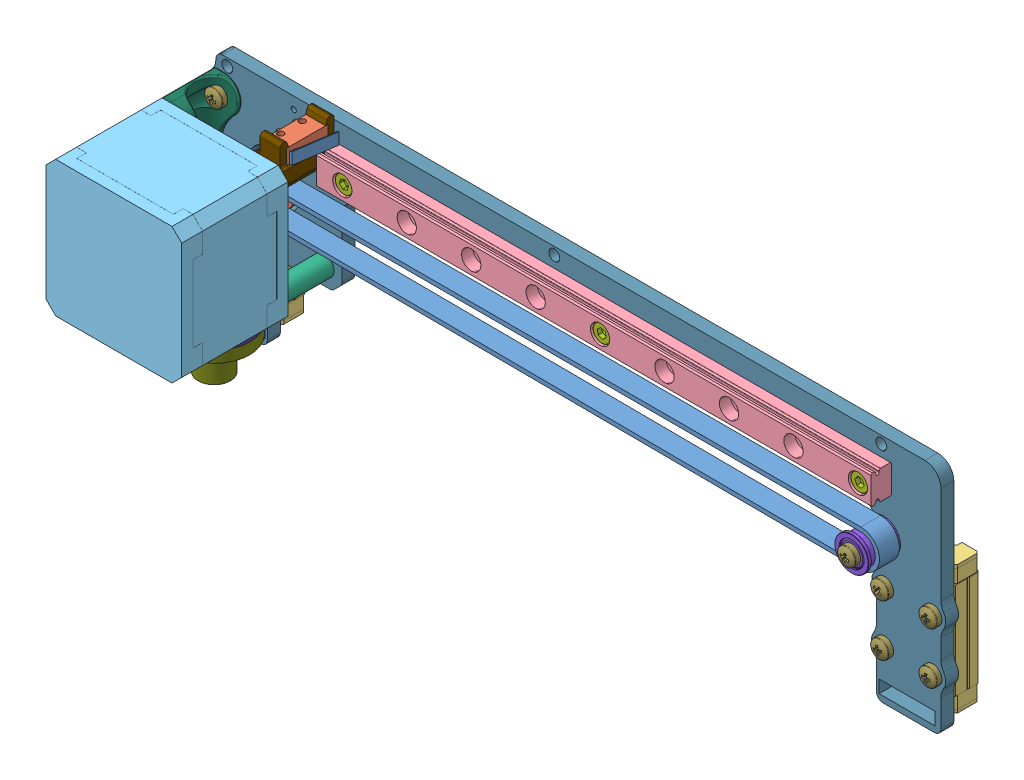
SolidWorks assembly X Bridge assembly mirror2, configuration Valor predeterminado. Lengths in mm.
Overall size (239.98 80.93 61.8).
47 component instances, 20 part files, 82 mates.
Components (placement in the parent):
- Mini CF X Belt (MXL)-2: Mini CF X Belt (MXL) [Default] at (-299.1991 -275.8743 16.2803) x (0.005742 0.999984 0) z (0 0 1) size (11.6 200.95 6.2)
- Timing Gear 15 touth MXL-2: Timing Gear 15 touth MXL [Valor predeterminado] at (-184.7535 53.485 6.1803) x (0 0 1) z (-0.766371 -0.642398 0) size (14.3 14.8 14.8)
- Rail MGN9-4: Rail MGN9 [Default] at (-196.8317 30.5 0.9403) x (-1 0 0) z (0 1 0) size (20 8.06 39.97)
- Mini CF TRACK-2: Mini CF TRACK [Valor predeterminado] at (-347.093 68.74 8.4403) x (0 -1 0) z (0 0 1) size (9 171.98 6.5)
- Steper Motor (42HD0401-24, 34mm)-2: Steper Motor (42HD0401-24, 34mm) [Default] at (-184.7535 53.485 58.1803) x (0 1 0) z (0 0 -1) size (42.1 42.1 48.5)
- Rail MGN9-5: Rail MGN9 [Default] at (12.172 30.5 0.9403) x (-1 0 0) z (0 1 0) size (20 8.06 39.97)
- Mini CF X Bridge spacer-4: Mini CF X Bridge spacer [Valor predeterminado] at (-191.3535 42.9506 25.1803) x (0.844919 0.534894 0) z (0 0 -1) size (6.2 6.2 16.74)
- ISO 4762 M3 x 10 --- 10N-4: ISO 4762 M3 x 10 --- 10N [ISO 4762 M3 x 8 --- 8N] at (2.907 68.74 14.4403) x (0 0 -1) z (-0.081652 -0.996661 0) size (11 5.5 5.5)
- ISO 4762 M3 x 10 --- 10N-5: ISO 4762 M3 x 10 --- 10N [ISO 4762 M3 x 8 --- 8N] at (-77.093 68.74 14.4403) x (0 0 -1) z (-0.673418 0.739262 0) size (11 5.5 5.5)
- ISO 4762 M3 x 10 --- 10N-6: ISO 4762 M3 x 10 --- 10N [ISO 4762 M3 x 8 --- 8N] at (-157.093 68.74 14.4403) x (0 0 -1) z (-0.266118 0.96394 0) size (11 5.5 5.5)
- Bearing assembly-2: Bearing assembly [Default] at (5.1399 52.94 11.6421) x (0 0 -1) z (-0.016512 -0.999864 0) size (10.71 13.72 13.72)
  - F603HZZ-1: F603HZZ [Default] at origin size (5 10.49 10.49)
    - F603HZZ_SOLID_1-1: F603HZZ_SOLID_1 [Default] at origin size (5 10.49 10.49)
    - F603HZZ_SOLID_2-1: F603HZZ_SOLID_2 [Default] at origin size (3.13 7.92 8.2)
    - F603HZZ_SOLID_3-1: F603HZZ_SOLID_3 [Default] at origin size (5 4.24 4.24)
  - F603HZZ-2: F603HZZ [Default] at (-5.0038 0 0) x (-1 0 0) z (0 -0.922978 -0.384852) size (5 10.49 10.49)
    - F603HZZ_SOLID_1-1: F603HZZ_SOLID_1 [Default] at origin size (5 10.49 10.49)
    - F603HZZ_SOLID_2-1: F603HZZ_SOLID_2 [Default] at origin size (3.13 7.92 8.2)
    - F603HZZ_SOLID_3-1: F603HZZ_SOLID_3 [Default] at origin size (5 4.24 4.24)
  - plain washer 10673 type snl_iso-1: plain washer 10673 type snl_iso [ISO 10673-3.2-S] at (2.4018 0 0) x (1 0 0) z (0 0.016518 0.999864) size (0.8 7 7)
- ISO 7045 - M3 x 20 - Z --- 20N-33: ISO 7045 - M3 x 20 - Z --- 20N [ISO 7045 - M3 x 16 - Z --- 16N] at (5.1399 52.94 21.5478) x (0 0 -1) z (-0.206204 -0.978509 0) size (18.35 5.6 5.6)
- hex thin nut chamfered gradeab_iso-7: hex thin nut chamfered gradeab_iso [Hexagon Thin Nut ISO - 4035 - M3 - N] at (2.907 68.74 2.6403) x (0.999802 0.019878 0) z (0 0 -1) size (5.5 6.35 1.8)
- hex thin nut chamfered gradeab_iso-8: hex thin nut chamfered gradeab_iso [Hexagon Thin Nut ISO - 4035 - M3 - N] at (-77.093 68.74 2.6403) x (0.866237 0.499633 0) z (0 0 -1) size (5.5 6.35 1.8)
- hex thin nut chamfered gradeab_iso-9: hex thin nut chamfered gradeab_iso [Hexagon Thin Nut ISO - 4035 - M3 - N] at (5.1399 52.94 2.6403) x (0.866025 0.5 0) z (0 0 -1) size (5.5 6.35 1.8)
- ISO 7045 - M3 x 20 - Z --- 20N-34: ISO 7045 - M3 x 20 - Z --- 20N [ISO 7045 - M3 x 6 - Z --- 6N] at (-204.3317 22.5 10.8403) x (0 0 -1) z (-0.901363 0.433064 0) size (8.35 5.6 5.6)
- ISO 7045 - M3 x 20 - Z --- 20N-35: ISO 7045 - M3 x 20 - Z --- 20N [ISO 7045 - M3 x 6 - Z --- 6N] at (-204.3317 38.5 10.8403) x (0 0 -1) z (0.229638 -0.973276 0) size (8.35 5.6 5.6)
- ISO 7045 - M3 x 20 - Z --- 20N-36: ISO 7045 - M3 x 20 - Z --- 20N [ISO 7045 - M3 x 6 - Z --- 6N] at (-189.2615 38.4288 10.8403) x (0 0 -1) z (-0.98537 -0.170431 0) size (8.35 5.6 5.6)
- ISO 7045 - M3 x 20 - Z --- 20N-37: ISO 7045 - M3 x 20 - Z --- 20N [ISO 7045 - M3 x 6 - Z --- 6N] at (-189.3317 22.5 10.8403) x (0 0 -1) z (0.979425 0.201808 0) size (8.35 5.6 5.6)
- ISO 7045 - M3 x 20 - Z --- 20N-38: ISO 7045 - M3 x 20 - Z --- 20N [ISO 7045 - M3 x 6 - Z --- 6N] at (19.672 22.5 10.8403) x (0 0 -1) z (0.000007 -1 0) size (8.35 5.6 5.6)
- ISO 7045 - M3 x 20 - Z --- 20N-39: ISO 7045 - M3 x 20 - Z --- 20N [ISO 7045 - M3 x 6 - Z --- 6N] at (4.672 38.5 10.8403) x (0 0 -1) z (-0.506009 -0.862528 0) size (8.35 5.6 5.6)
- ISO 7045 - M3 x 20 - Z --- 20N-40: ISO 7045 - M3 x 20 - Z --- 20N [ISO 7045 - M3 x 6 - Z --- 6N] at (4.672 22.5 10.8403) x (0 0 -1) z (0.179665 -0.983728 0) size (8.35 5.6 5.6)
- ISO 7045 - M3 x 20 - Z --- 20N-41: ISO 7045 - M3 x 20 - Z --- 20N [ISO 7045 - M3 x 6 - Z --- 6N] at (19.672 38.5 10.8403) x (0 0 -1) z (0.000007 -1 0) size (8.35 5.6 5.6)
- ISO 7045 - M3 x 20 - Z --- 20N-42: ISO 7045 - M3 x 20 - Z --- 20N [ISO 7045 - M3 x 25 - Z --- 25N] at (-169.2535 37.985 2.0403) x (0 0 1) z (-0.966631 -0.256173 0) size (27.35 5.6 5.6)
- ISO 7045 - M3 x 20 - Z --- 20N-43: ISO 7045 - M3 x 20 - Z --- 20N [ISO 7045 - M3 x 25 - Z --- 25N] at (-169.2535 68.985 2.0403) x (0 0 1) z (0.45862 0.888632 0) size (27.35 5.6 5.6)
- ISO 7045 - M3 x 20 - Z --- 20N-44: ISO 7045 - M3 x 20 - Z --- 20N [ISO 7045 - M3 x 12 - Z --- 12N] at (-200.2535 37.985 19.7803) x (0 0 1) z (0.558384 0.829583 0) size (14.35 5.6 5.6)
- ISO 7045 - M3 x 20 - Z --- 20N-45: ISO 7045 - M3 x 20 - Z --- 20N [ISO 7045 - M3 x 10 - Z --- 10N] at (-200.2535 68.985 19.7803) x (0 0 1) z (-0.999173 0.040658 0) size (12.35 5.6 5.6)
- ISO 7045 - M3 x 20 - Z --- 20N-46: ISO 7045 - M3 x 20 - Z --- 20N [ISO 7045 - M3 x 8 - Z --- 8N] at (-200.2535 68.985 12.5803) x (0 0 -1) z (0.986089 -0.166217 0) size (10.35 5.6 5.6)
- hex thin nut chamfered gradeab_iso-10: hex thin nut chamfered gradeab_iso [Hexagon Thin Nut ISO - 4035 - M3 - N] at (-157.093 68.74 2.6403) x (-0.706351 -0.707861 0) z (0 0 -1) size (5.5 6.35 1.8)
- Mini CF X Bridge 4-1: Mini CF X Bridge 4 [Valor predeterminado] at (-92.8769 -11.1773 8.4403) x (-1 0 0) z (0 0 -1) size (232.81 71.67 4)
- Mini CF X Motor atachment mirror-1: Mini CF X Motor atachment mirror [Valor predeterminado] at (-92.8769 76.0473 25.1803) x (1 0 0) z (0 0 -1) size (11.14 42.1 17.27)
- Treaded Rod Female assembly-1: Treaded Rod Female assembly [Default] at (-40.0999 9.3907 170.362) x (0.703961 0 -0.710239) z (0 1 0) size (28.31 28.33 17.5)
  - Mini CF Z Treaded Rod Female Special Nut-1: Mini CF Z Treaded Rod Female Special Nut [Default] at origin size (22 22 13.5)
  - Mini CF Z nut atachment-1: Mini CF Z nut atachment [Valor predeterminado] at (142.1229 506.6992 3.5) x (0.703961 -0.710239 0) z (0 0 1) size (22 18.05 4)
- Mini CF X Bridge spacer FOR ENDSTOP-1: Mini CF X Bridge spacer FOR ENDSTOP [Valor predeterminado] at (-153.2368 52.9683 25.1803) x (-1 0 0) z (0 0 -1) size (9.2 14.43 16.74)
- Endstop Assembly (HT-010-1A-250VAC) - small-1: Endstop Assembly (HT-010-1A-250VAC) - small [Default] at (-173.3998 75.5732 12.0816) x (0 0 -1) z (0 -1 0) size (13.8 11.8 5.71)
  - Endstop Actuator (HT-010-1A-250VAC)-1: Endstop Actuator (HT-010-1A-250VAC) [Default] at (-9.3436 7.5264 -0.1798) size (12.8 2.57 3.6)
  - Enstop Base (HT-010-1A-250VAC)-1: Enstop Base (HT-010-1A-250VAC) [Default] at (-1.4636 2.6194 0.1552) size (12.83 9.86 5.71)
Mates (geometry in assembly coordinates):
- Tangente3: tangent: plane of Mini CF X Belt (MXL)-2; cylinder of Timing Gear 15 touth MXL-2 through (0.0938 53.4854 18.24) axis (0 0 -1) radius 3.955
- Concêntrico19: concentric: cylinder of Mini CF X Belt (MXL)-2 through (0.0938 53.4854 5.7905) axis (0 0 1) radius 5.2546; cylinder of Timing Gear 15 touth MXL-2 through (0.0938 53.4854 18.24) axis (0 0 -1) radius 7.4
- Paralelo2: parallel: plane of Mini CF X Belt (MXL)-2; plane of Mini CF TRACK-2 through (652.907 64.24 8.4403) normal (0 -1 0)
- Concentric401058: concentric anti-aligned: cylinder of Mini CF X Belt (MXL)-2 through (-184.7534 53.485 10.0803) axis (0 0 1) radius 3.9546; cylinder of Timing Gear 15 touth MXL-2 through (-184.7535 53.485 22.6803) axis (0 0 -1) radius 7.4
- Distance1: distance = 0.7 mm anti-aligned: plane of Mini CF X Belt (MXL)-2 through (5.1399 52.94 10.0803) normal (0 0 -1); plane of Timing Gear 15 touth MXL-2 through (-189.5072 59.1561 9.3803) normal (0 0 1)
- Concentric401066: concentric anti-aligned: cylinder of Mini CF X Belt (MXL)-2 through (5.1399 52.94 10.0803) axis (0 0 1) radius 4.5; cylinder of Bearing assembly-2/F603HZZ-1/F603HZZ_SOLID_1-1 through (5.1399 52.94 14.3942) axis (0 0 -1) radius 4.4958
- Distance4: distance = 0.1 mm anti-aligned: plane of Mini CF X Belt (MXL)-2 through (-369.8613 52.9396 10.2308) normal (0 0 -1); plane of Bearing assembly-2/F603HZZ-1/F603HZZ_SOLID_1-1 through (5.1399 52.94 10.1308) normal (0 0 1)
- Coincident7871313: coincident: plane of Mini CF X Belt (MXL)-2 through (-185.014 52.94 11.9905) normal (0 0 1); plane of ? through (-185.014 52.94 13.7169) normal (0 0 -1)
- Distância12: distance = 2 mm: plane of Steper Motor (42HD0401-24, 34mm)-2 through (0.0938 53.4854 18.74) normal (0 0 -1); plane of Timing Gear 15 touth MXL-2 through (0.0938 53.4854 3.94) normal (0 0 -1)
- Concêntrico37: concentric aligned: cylinder of Timing Gear 15 touth MXL-2 through (-184.7535 53.485 22.6803) axis (0 0 1) radius 2.5; cylinder of Steper Motor (42HD0401-24, 34mm)-2 through (-184.7535 53.485 9.6803) axis (0 0 1) radius 2.5
- Distance3: distance = 0.5 mm anti-aligned: plane of Timing Gear 15 touth MXL-2 through (-189.5072 59.1561 22.6803) normal (0 0 1); plane of Steper Motor (42HD0401-24, 34mm)-2 through (-184.7535 53.485 23.1803) normal (0 0 -1)
- Concentric401076: concentric anti-aligned: cylinder of Rail MGN9-4 through (-204.3317 22.5 4.4403) axis (0 0 -1) radius 1.25; cylinder of ISO 7045 - M3 x 20 - Z --- 20N-34 through (-204.3317 22.5 36.2403) axis (0 0 1) radius 1.5
- Concêntrico38: concentric aligned: cylinder of Mini CF TRACK-2 through (2.907 68.74 14.9403) axis (0 0 1) radius 3; cylinder of ISO 4762 M3 x 10 --- 10N-4 through (2.907 68.74 46.1903) axis (0 0 1) radius 2.75
- Coincidente189: coincident anti-aligned: plane of Mini CF TRACK-2 through (2.907 66.99 11.4403) normal (0 0 1); plane of ISO 4762 M3 x 10 --- 10N-4 through (5.6478 68.5155 11.4403) normal (0 0 -1)
- Concêntrico39: concentric aligned: cylinder of Mini CF TRACK-2 through (-77.093 68.74 14.9403) axis (0 0 1) radius 3; cylinder of ISO 4762 M3 x 10 --- 10N-5 through (-77.093 68.74 46.1903) axis (0 0 1) radius 2.75
- Coincidente190: coincident anti-aligned: plane of Mini CF TRACK-2 through (-77.093 66.99 11.4403) normal (0 0 1); plane of ISO 4762 M3 x 10 --- 10N-5 through (-79.126 66.8881 11.4403) normal (0 0 -1)
- Concêntrico40: concentric aligned: cylinder of Mini CF TRACK-2 through (-157.093 68.74 14.9403) axis (0 0 1) radius 1.75; cylinder of ISO 4762 M3 x 10 --- 10N-6 through (-157.093 68.74 46.1903) axis (0 0 1) radius 2.75
- Coincidente191: coincident anti-aligned: plane of Mini CF TRACK-2 through (-157.093 66.99 11.4403) normal (0 0 1); plane of ISO 4762 M3 x 10 --- 10N-6 through (-159.7439 68.0082 11.4403) normal (0 0 -1)
- Concêntrico28: concentric anti-aligned: circle of Steper Motor (42HD0401-24, 34mm)-2; circle of Mini CF X Bridge spacer-4
- Concêntrico35: concentric aligned: circle of Steper Motor (42HD0401-24, 34mm)-2; cylinder of Mini CF X Bridge spacer-4 through (-169.2535 37.985 8.4403) axis (0 0 1) radius 3.1
- Concentric401065: concentric aligned: cylinder of ISO 7045 - M3 x 20 - Z --- 20N-33 through (5.1399 52.94 46.9478) axis (0 0 1) radius 1.5; cylinder of Bearing assembly-2/plain washer 10673 type snl_iso-1 through (5.1399 52.94 8.4403) axis (0 0 1) radius 1.6
- Concentric401068: concentric aligned: cylinder of Bearing assembly-2/F603HZZ-2/F603HZZ_SOLID_3-1 through (5.1399 52.94 13.8938) axis (0 0 1) radius 1.4986; cylinder of ISO 7045 - M3 x 20 - Z --- 20N-33 through (5.1399 52.94 46.9478) axis (0 0 1) radius 2.8
- Coincident7871314: coincident anti-aligned: plane of ? through (5.1399 52.94 19.1478) normal (0 0 1); plane of ISO 7045 - M3 x 20 - Z --- 20N-33 through (6.6077 52.6307 19.1478) normal (0 0 -1)
- Parallel3: parallel: plane of Mini CF TRACK-2; plane of Mini CF X Bridge 4-1 through (-92.8769 78.74 4.4403) normal (0 1 0)
- Coincident7871363: coincident anti-aligned: plane of Mini CF TRACK-2 through (652.907 73.24 8.4403) normal (0 0 -1); plane of Mini CF X Bridge 4-1 through (-92.8769 -11.1773 8.4403) normal (0 0 1)
- Concentric401135: concentric anti-aligned: cylinder of ISO 7045 - M3 x 20 - Z --- 20N-35 through (-204.3317 38.5 36.2403) axis (0 0 1) radius 1.5; cylinder of Mini CF X Bridge 4-1 through (-204.3317 38.5 4.4403) axis (0 0 -1) radius 1.6
- Lock2: lock: unknown of Rail MGN9-5; unknown of Mini CF X Bridge 4-1
- Lock3: lock: unknown of Mini CF TRACK-2; unknown of Mini CF X Bridge 4-1
- Lock4: lock: unknown of Rail MGN9-4; unknown of Mini CF X Bridge 4-1
- Concentric401136: concentric aligned: cylinder of ISO 7045 - M3 x 20 - Z --- 20N-33 through (5.1399 52.94 46.9478) axis (0 0 1) radius 1.5; cylinder of Mini CF X Bridge 4-1 through (5.1399 52.94 8.4403) axis (0 0 1) radius 1.6
- Coincident7871368: coincident anti-aligned: plane of Bearing assembly-2/plain washer 10673 type snl_iso-1 through (5.1399 52.94 8.4403) normal (0 0 -1); plane of Mini CF X Bridge 4-1 through (-92.8769 -11.1773 8.4403) normal (0 0 1)
- Concentric401138: concentric anti-aligned: cylinder of Timing Gear 15 touth MXL-2 through (-184.7535 53.485 22.6803) axis (0 0 -1) radius 7.4; cylinder of Mini CF X Bridge 4-1 through (-184.7535 53.485 -1.5597) axis (0 0 1) radius 8.4
- Concentric401142: concentric anti-aligned: cylinder of ISO 4762 M3 x 10 --- 10N-4 through (2.907 68.74 46.1903) axis (0 0 1) radius 1.5; cylinder of Mini CF X Bridge 4-1 through (2.907 68.74 4.4403) axis (0 0 -1) radius 1.6
- Concentric401143: concentric anti-aligned: cylinder of ISO 4762 M3 x 10 --- 10N-6 through (-157.093 68.74 46.1903) axis (0 0 1) radius 1.5; cylinder of Mini CF X Bridge 4-1 through (-157.093 68.74 4.4403) axis (0 0 -1) radius 1.6
- Concentric401144: concentric anti-aligned: cylinder of ISO 7045 - M3 x 20 - Z --- 20N-43 through (-169.2535 68.985 -23.3597) axis (0 0 -1) radius 1.5; cylinder of Mini CF X Bridge 4-1 through (-169.2535 68.985 8.4403) axis (0 0 1) radius 1.6
- Coincident7871370: coincident anti-aligned: plane of ISO 7045 - M3 x 20 - Z --- 20N-43 through (-167.9205 68.2971 4.4403) normal (0 0 1); plane of Mini CF X Bridge 4-1 through (-92.8769 -11.1773 4.4403) normal (0 0 -1)
- Coincident7871371: coincident anti-aligned: plane of Mini CF X Bridge spacer-4 through (-169.2535 37.985 8.4403) normal (0 0 -1); plane of Mini CF X Bridge 4-1 through (-92.8769 -11.1773 8.4403) normal (0 0 1)
- Concentric401145: concentric anti-aligned: cylinder of ISO 7045 - M3 x 20 - Z --- 20N-42 through (-169.2535 37.985 -23.3597) axis (0 0 -1) radius 1.5; cylinder of Mini CF X Bridge 4-1 through (-169.2535 37.985 8.4403) axis (0 0 1) radius 1.6
- Coincident7871372: coincident anti-aligned: plane of ISO 7045 - M3 x 20 - Z --- 20N-42 through (-169.6377 39.4349 4.4403) normal (0 0 1); plane of Mini CF X Bridge 4-1 through (-92.8769 -11.1773 4.4403) normal (0 0 -1)
- Concentric401146: concentric anti-aligned: cylinder of ISO 4762 M3 x 10 --- 10N-5 through (-77.093 68.74 46.1903) axis (0 0 1) radius 1.5; cylinder of hex thin nut chamfered gradeab_iso-8 through (-77.093 68.74 4.4403) axis (0 0 -1) radius 1.25
- Concentric401147: concentric anti-aligned: cylinder of ISO 4762 M3 x 10 --- 10N-4 through (2.907 68.74 46.1903) axis (0 0 1) radius 1.5; cylinder of hex thin nut chamfered gradeab_iso-7 through (2.907 68.74 4.4403) axis (0 0 -1) radius 1.25
- Concentric401148: concentric anti-aligned: circle of ISO 4762 M3 x 10 --- 10N-6; cylinder of hex thin nut chamfered gradeab_iso-10 through (-157.093 68.74 4.4403) axis (0 0 -1) radius 1.25
- Concentric401149: concentric aligned: cylinder of ISO 7045 - M3 x 20 - Z --- 20N-33 through (5.1399 52.94 46.9478) axis (0 0 1) radius 1.5; circle of hex thin nut chamfered gradeab_iso-9
- Coincident7871374: coincident anti-aligned: plane of hex thin nut chamfered gradeab_iso-7 through (2.9701 65.5652 4.4403) normal (0 0 1); plane of Mini CF X Bridge 4-1 through (-92.8769 -11.1773 4.4403) normal (0 0 -1)
- Coincident7871375: coincident anti-aligned: plane of hex thin nut chamfered gradeab_iso-9 through (6.7276 50.19 4.4403) normal (0 0 1); plane of Mini CF X Bridge 4-1 through (-92.8769 -11.1773 4.4403) normal (0 0 -1)
- Coincident7871376: coincident anti-aligned: plane of hex thin nut chamfered gradeab_iso-8 through (-75.5065 65.9893 4.4403) normal (0 0 1); plane of Mini CF X Bridge 4-1 through (-92.8769 -11.1773 4.4403) normal (0 0 -1)
- Coincident7871377: coincident anti-aligned: plane of hex thin nut chamfered gradeab_iso-10 through (-159.3408 70.983 4.4403) normal (0 0 1); plane of Mini CF X Bridge 4-1 through (-92.8769 -11.1773 4.4403) normal (0 0 -1)
- Concentric401150: concentric anti-aligned: cylinder of ISO 7045 - M3 x 20 - Z --- 20N-37 through (-189.3317 22.5 36.2403) axis (0 0 1) radius 1.5; cylinder of Mini CF X Bridge 4-1 through (-189.3317 22.5 4.4403) axis (0 0 -1) radius 1.6
- Concentric401151: concentric anti-aligned: cylinder of ISO 7045 - M3 x 20 - Z --- 20N-34 through (-204.3317 22.5 36.2403) axis (0 0 1) radius 1.5; cylinder of Mini CF X Bridge 4-1 through (-204.3317 22.5 4.4403) axis (0 0 -1) radius 1.6
- Coincident7871378: coincident anti-aligned: plane of ISO 7045 - M3 x 20 - Z --- 20N-34 through (-204.9813 21.148 8.4403) normal (0 0 -1); plane of Mini CF X Bridge 4-1 through (-92.8769 -11.1773 8.4403) normal (0 0 1)
- Coincident7871379: coincident anti-aligned: plane of ISO 7045 - M3 x 20 - Z --- 20N-37 through (-189.6344 23.9691 8.4403) normal (0 0 -1); plane of Mini CF X Bridge 4-1 through (-92.8769 -11.1773 8.4403) normal (0 0 1)
- Tangent5: tangent aligned: cylinder of ISO 7045 - M3 x 20 - Z --- 20N-36 through (-189.2615 38.4288 36.2403) axis (0 0 1) radius 1.5; cylinder of Mini CF X Bridge 4-1 through (-189.3317 38.5 4.4403) axis (0 0 -1) radius 1.6
- Coincident7871380: coincident anti-aligned: plane of ISO 7045 - M3 x 20 - Z --- 20N-36 through (-189.0058 36.9507 8.4403) normal (0 0 -1); plane of Mini CF X Bridge 4-1 through (-92.8769 -11.1773 8.4403) normal (0 0 1)
- Coincident7871381: coincident anti-aligned: plane of Steper Motor (42HD0401-24, 34mm)-2 through (-163.7035 74.535 25.1803) normal (0 0 -1); plane of Mini CF X Motor atachment mirror-1 through (-200.2535 37.985 25.1803) normal (0 0 1)
- Concentric401152: concentric aligned: cylinder of ISO 7045 - M3 x 20 - Z --- 20N-44 through (-200.2535 37.985 -5.6197) axis (0 0 -1) radius 1.5; cylinder of Mini CF X Motor atachment mirror-1 through (-200.2535 37.985 8.4403) axis (0 0 -1) radius 1.6
- Concentric401153: concentric aligned: cylinder of Steper Motor (42HD0401-24, 34mm)-2 through (-200.2535 37.985 25.1803) axis (0 0 -1) radius 1.25; cylinder of ISO 7045 - M3 x 20 - Z --- 20N-44 through (-200.2535 37.985 -5.6197) axis (0 0 -1) radius 1.5
- Concentric401154: concentric aligned: cylinder of Steper Motor (42HD0401-24, 34mm)-2 through (-200.2535 68.985 25.1803) axis (0 0 -1) radius 1.25; cylinder of Mini CF X Motor atachment mirror-1 through (-200.2535 68.985 8.4403) axis (0 0 -1) radius 1.6
- Coincident7871382: coincident anti-aligned: plane of ISO 7045 - M3 x 20 - Z --- 20N-46 through (-200.0042 70.4641 10.1803) normal (0 0 -1); plane of Mini CF X Motor atachment mirror-1 through (-200.2535 68.985 10.1803) normal (0 0 1)
- Concentric401155: concentric anti-aligned: cylinder of ISO 7045 - M3 x 20 - Z --- 20N-46 through (-200.2535 68.985 37.9803) axis (0 0 1) radius 1.5; cylinder of Mini CF X Motor atachment mirror-1 through (-200.2535 68.985 8.4403) axis (0 0 -1) radius 1.6
- Coincident7871383: coincident anti-aligned: plane of ISO 7045 - M3 x 20 - Z --- 20N-45 through (-200.1925 70.4838 22.1803) normal (0 0 1); plane of Mini CF X Motor atachment mirror-1 through (-200.2535 68.985 22.1803) normal (0 0 -1)
- Coincident7871384: coincident anti-aligned: plane of ISO 7045 - M3 x 20 - Z --- 20N-44 through (-199.0091 37.1474 22.1803) normal (0 0 1); plane of Mini CF X Motor atachment mirror-1 through (-200.2535 37.985 22.1803) normal (0 0 -1)
- Coincident7871385: coincident anti-aligned: plane of Mini CF X Bridge 4-1 through (-92.8769 -11.1773 8.4403) normal (0 0 1); plane of Mini CF X Motor atachment mirror-1 through (-92.8769 -11.1773 8.4403) normal (0 0 -1)
- Coincident7871386: coincident anti-aligned: plane of ISO 7045 - M3 x 20 - Z --- 20N-35 through (-202.8718 38.8445 8.4403) normal (0 0 -1); plane of Mini CF X Bridge 4-1 through (-92.8769 -11.1773 8.4403) normal (0 0 1)
- Concentric401156: concentric aligned: cylinder of ISO 7045 - M3 x 20 - Z --- 20N-45 through (-200.2535 68.985 -5.6197) axis (0 0 -1) radius 1.5; cylinder of Mini CF X Motor atachment mirror-1 through (-200.2535 68.985 8.4403) axis (0 0 -1) radius 1.6
- Concentric401157: concentric anti-aligned: cylinder of ISO 7045 - M3 x 20 - Z --- 20N-40 through (4.672 22.5 36.2403) axis (0 0 1) radius 1.5; cylinder of Mini CF X Bridge 4-1 through (4.672 22.5 4.4403) axis (0 0 -1) radius 1.6
- Concentric401158: concentric anti-aligned: cylinder of ISO 7045 - M3 x 20 - Z --- 20N-38 through (19.672 22.5 36.2403) axis (0 0 1) radius 1.5; cylinder of Mini CF X Bridge 4-1 through (19.672 22.5 4.4403) axis (0 0 -1) radius 1.6
- Concentric401159: concentric anti-aligned: cylinder of ISO 7045 - M3 x 20 - Z --- 20N-41 through (19.672 38.5 36.2403) axis (0 0 1) radius 1.5; cylinder of Mini CF X Bridge 4-1 through (19.672 38.5 4.4403) axis (0 0 -1) radius 1.6
- Concentric401160: concentric anti-aligned: cylinder of ISO 7045 - M3 x 20 - Z --- 20N-39 through (4.672 38.5 36.2403) axis (0 0 1) radius 1.5; cylinder of Mini CF X Bridge 4-1 through (4.672 38.5 4.4403) axis (0 0 -1) radius 1.6
- Coincident7871388: coincident anti-aligned: plane of ISO 7045 - M3 x 20 - Z --- 20N-39 through (5.9658 37.741 8.4403) normal (0 0 -1); plane of Mini CF X Bridge 4-1 through (-92.8769 -11.1773 8.4403) normal (0 0 1)
- Coincident7871389: coincident anti-aligned: plane of ISO 7045 - M3 x 20 - Z --- 20N-41 through (21.172 38.5 8.4403) normal (0 0 -1); plane of Mini CF X Bridge 4-1 through (-92.8769 -11.1773 8.4403) normal (0 0 1)
- Coincident7871390: coincident anti-aligned: plane of ISO 7045 - M3 x 20 - Z --- 20N-38 through (21.172 22.5 8.4403) normal (0 0 -1); plane of Mini CF X Bridge 4-1 through (-92.8769 -11.1773 8.4403) normal (0 0 1)
- Coincident7871391: coincident anti-aligned: plane of ISO 7045 - M3 x 20 - Z --- 20N-40 through (6.1476 22.7695 8.4403) normal (0 0 -1); plane of Mini CF X Bridge 4-1 through (-92.8769 -11.1773 8.4403) normal (0 0 1)
- Parallel4: parallel aligned: plane of hex thin nut chamfered gradeab_iso-9 through (3.5522 55.69 4.4403) normal (0 1 0); plane of Mini CF X Bridge 4-1 through (-92.8769 78.74 4.4403) normal (0 1 0)
- Parallel5: parallel aligned: plane of Mini CF X Belt (MXL)-2; plane of Mini CF TRACK-2 through (652.907 73.24 14.4519) normal (0 1 0)
- Coincident787188: coincident anti-aligned: plane of Mini CF X Bridge 4-1 through (-92.8769 -11.1773 8.4403) normal (0 0 1); plane of Treaded Rod Female assembly-1/Mini CF Z nut atachment-1 through (-204.7255 16.8907 8.4403) normal (0 0 -1)
- Coincident787189: coincident anti-aligned: plane of Mini CF X Bridge 4-1 through (-187.6352 12.8907 17.4403) normal (0 -1 0); plane of Treaded Rod Female assembly-1/Mini CF Z Treaded Rod Female Special Nut-1 through (-40.0999 12.8907 170.362) normal (0 1 0)
- Coincident787241: coincident anti-aligned: plane of Mini CF X Bridge 4-1 through (-92.8769 -11.1773 8.4403) normal (0 0 1); plane of Mini CF X Bridge spacer FOR ENDSTOP-1 through (-169.2535 68.985 8.4403) normal (0 0 -1)
- Concentric401181: concentric anti-aligned: cylinder of ISO 7045 - M3 x 20 - Z --- 20N-43 through (-169.2535 68.985 -23.3597) axis (0 0 -1) radius 1.5; cylinder of Mini CF X Bridge spacer FOR ENDSTOP-1 through (-169.2535 68.985 8.4403) axis (0 0 1) radius 1.55
- Parallel19: parallel aligned: plane of Mini CF X Bridge 4-1 through (-92.8769 78.74 4.4403) normal (0 1 0); plane of Mini CF X Bridge spacer FOR ENDSTOP-1 through (-166.1535 72.603 1.2618) normal (0 1 0)
- Coincident787249: coincident anti-aligned: plane of Mini CF X Bridge spacer FOR ENDSTOP-1 through (-166.1535 72.603 1.2618) normal (0 1 0); plane of Endstop Assembly (HT-010-1A-250VAC) - small-1/Enstop Base (HT-010-1A-250VAC)-1 through (-166.1535 72.603 23.2253) normal (0 -1 0)
- Coincident787250: coincident anti-aligned: plane of Mini CF X Bridge spacer FOR ENDSTOP-1 through (-166.1535 88.8189 23.2253) normal (0 0 -1); plane of Endstop Assembly (HT-010-1A-250VAC) - small-1/Enstop Base (HT-010-1A-250VAC)-1 through (-172.2805 78.318 23.2253) normal (0 0 1)
- Coincident787251: coincident anti-aligned: plane of Mini CF X Bridge spacer FOR ENDSTOP-1 through (-166.1535 52.9683 25.1803) normal (-1 0 0); plane of Endstop Assembly (HT-010-1A-250VAC) - small-1/Enstop Base (HT-010-1A-250VAC)-1 through (-166.1535 78.318 23.2253) normal (1 0 0)
